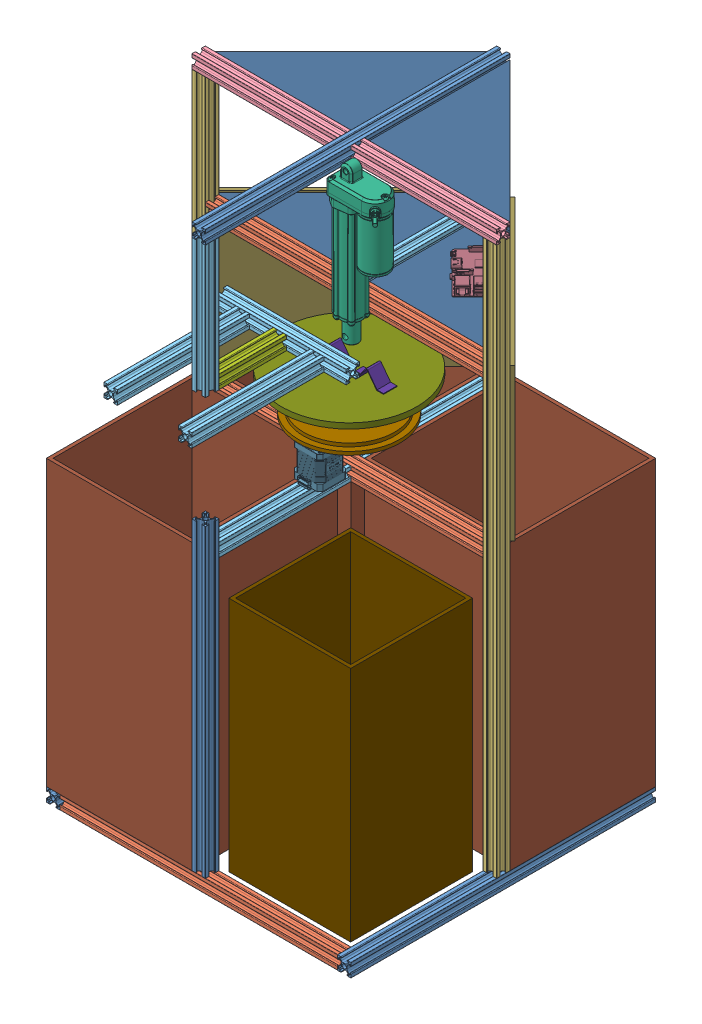
SolidWorks assembly 垃圾分类装配11.12, configuration 默认. Lengths in mm.
Overall size (454.8 850 529.91).
41 component instances, 18 part files, 92 mates.
Components (placement in the parent):
- 型材-1: 型材 [默认] at origin size (20 20 450)
- 型材-2: 型材 [默认] at (430 0 0) size (20 20 450)
- 450-40型材-1: 450-40型材 [默认] at (60 0 390) x (0 0 -1) z (1 0 0) size (20 20 410)
- 450-40型材-2: 450-40型材 [默认] at (60 0 -40) x (0 0 -1) z (1 0 0) size (20 20 410)
- 850-40型材-1: 850-40型材 [默认] at (0 770 175) x (1 0 0) z (0 -1 0) size (20 20 810)
- 850-40型材-2: 850-40型材 [默认] at (430 770 175) x (1 0 0) z (0 -1 0) size (20 20 810)
- 850-40型材-3: 850-40型材 [默认] at (215 770 -40) x (1 0 0) z (0 -1 0) size (20 20 810)
- 型材-3: 型材 [默认] at (215 830 0) size (20 20 450)
- 215型材-1: 215型材 [默认] at (274.9999 830 175) x (0 0 -1) z (1 0 0) size (20 20 215)
- 215型材-2: 215型材 [默认] at (40 830 175) x (0 0 -1) z (1 0 0) size (20 20 215)
- 450-40型材-3: 450-40型材 [默认] at (60 650 175) x (0 0 -1) z (1 0 0) size (20 20 410)
- 195型材-1: 195型材 [默认] at (215 650 20) size (20 20 195)
- 电动推杆-1: 电动推杆 [默认] at (248.0139 794.0379 210.699) x (-1 0 0) z (0 -1 0) size (89.01 54.01 228.74)
- 450-40型材-4: 450-40型材 [默认] at (60 420 175) x (0 0 -1) z (1 0 0) size (20 20 410)
- 195型材-2: 195型材 [默认] at (215 420 20) size (20 20 195)
- 型材-4: 型材 [默认] at (215 410 390) x (-1 0 0) z (0 -1 0) size (20 20 450)
- 195型材-3: 195型材 [默认] at (215 420 235) size (20 20 195)
- 195型材-4: 195型材 [默认] at (215 770 390) x (1 0 0) z (0 -1 0) size (20 20 195)
- 100型材-1: 100型材 [默认] at (215 635 330) size (20 20 100)
- 195型材-5: 195型材 [默认] at (167.5 635 270.0001) x (0 -1 0) z (1 0 0) size (20 20 195)
- 195型材-6: 195型材 [默认] at (269.9999 635 330) size (20 20 195)
- 195型材-7: 195型材 [默认] at (160 635 330) size (20 20 195)
- 小电机-1: 小电机 [默认] at (197.0585 516.4999 164.8) x (0 0 1) z (0 1 0) size (53.6 47.6 20)
- 电机上面圆盘-1: 电机上面圆盘 [默认] at (213.1083 486.2499 175.9459) x (0.178496 0 0.983941) z (-0.983941 0 0.178496) size (150 15.5 150)
- 三角木板-1: 三角木板 [默认] at (205 647.5 165) x (0 0 -1) z (1 0 0) size (215 5 215)
- 三角木板-2: 三角木板 [默认] at (225 647.5 165) size (215 5 215)
- 三角木板-3: 三角木板 [默认] at (225 827.5 165) size (215 5 215)
- 三角木板-4: 三角木板 [默认] at (205 827.5 165) x (0 0 -1) z (1 0 0) size (215 5 215)
- 纸盒-1: 纸盒 [默认] at (97.5 10 57.5) size (215 420 215)
- 纸盒-2: 纸盒 [默认] at (97.5 10 292.5) size (215 420 215)
- 纸盒-3: 纸盒 [默认] at (332.5 10 57.5) size (215 420 215)
- 纸盒-4: 纸盒 [默认] at (332.5 10 292.5) size (215 420 215) (hidden)
- 矩形木板-1: 矩形木板 [默认] at (332.871 542.5 54.3356) x (0.707107 0 0.707107) z (-0.707107 0 0.707107) size (304 225 5)
- 矩形木板-2: 矩形木板 [默认] at (96.5624 542.5 54.9021) x (-0.707107 0 0.707107) z (-0.707107 0 -0.707107) size (304 225 5)
- 电路板-1: 电路板 [默认] at (300.8487 658.8 72.0727) x (0.707107 0 0.707107) z (-0.707107 0 0.707107) size (92.18 27.81 66.27)
- 小电机新主动-1: 小电机新主动 [默认] at (215.8438 429.9999 221.7279) x (1 0 0) z (0 1 0) size (42.21 46.5 63.1)
- 舵机转向机构-1: 舵机转向机构 [默认] at (218.5585 496.4999 174.8) size (48 41 20)
- 舵机上面圆盘-1: 舵机上面圆盘 [默认] at (213.1083 537.4999 175.9459) size (200 8 200)
- 三角件-1: 三角件 [默认] at (189.2957 545.4999 174.8) size (50 20.33 20)
- 三角件-2: 三角件 [默认] at (247.8213 545.4999 174.8) size (50 20.33 20)
- 纸盒2-1: 纸盒2 [默认] at (323.6542 10 284.153) size (180 350 180)
Mates (geometry in assembly coordinates):
- 重合1: coincident aligned: plane of 型材-1 through (9.6 10 0) normal (0 1 0); plane of 型材-2 through (424.85 10 0) normal (0 1 0)
- 重合2: coincident aligned: plane of 型材-1 through (0 0 400) normal (0 0 1); plane of 型材-2 through (430 0 400) normal (0 0 1)
- 重合3: coincident aligned: plane of 型材-1 through (9.6 10 0) normal (0 1 0); plane of 450-40型材-1 through (60 10 395.15) normal (0 1 0)
- 重合4: coincident anti-aligned: plane of 型材-1 through (10 5.15 0) normal (1 0 0); plane of 450-40型材-1 through (10 0 390) normal (-1 0 0)
- 重合5: coincident aligned: plane of 型材-1 through (0 0 400) normal (0 0 1); plane of 450-40型材-1 through (60 9.6 400) normal (0 0 1)
- 重合6: coincident anti-aligned: plane of 型材-2 through (420 9.6 0) normal (-1 0 0); plane of 450-40型材-1 through (420 0 390) normal (1 0 0)
- 重合7: coincident aligned: plane of 型材-1 through (0 0 -50) normal (0 0 -1); plane of 450-40型材-2 through (60 -9.6 -50) normal (0 0 -1)
- 重合8: coincident aligned: plane of 型材-1 through (9.6 10 0) normal (0 1 0); plane of 450-40型材-2 through (60 10 -49.6) normal (0 1 0)
- 重合9: coincident anti-aligned: plane of 型材-1 through (10 -9.6 0) normal (1 0 0); plane of 450-40型材-2 through (10 0 -40) normal (-1 0 0)
- 重合10: coincident aligned: plane of 型材-1 through (10 5.15 0) normal (1 0 0); plane of 850-40型材-1 through (10 770 180.15) normal (1 0 0)
- 重合11: coincident anti-aligned: plane of 型材-1 through (-5.15 10 0) normal (0 1 0); plane of 850-40型材-1 through (0 10 175) normal (0 -1 0)
- 宽度1: width aligned: plane of 型材-1 through (0 0 400) normal (0 0 1); plane of 型材-1 through (0 0 -50) normal (0 0 -1); plane of 850-40型材-1 through (9.6 770 185) normal (0 0 1); plane of 850-40型材-1 through (5.15 770 165) normal (0 0 -1)
- 重合12: coincident aligned: plane of 850-40型材-1 through (5.15 770 165) normal (0 0 -1); plane of 850-40型材-2 through (420.4 770 165) normal (0 0 -1)
- 重合13: coincident aligned: plane of 型材-2 through (439.9999 5.15 0) normal (1 0 0); plane of 850-40型材-2 through (439.9999 770 165.4) normal (1 0 0)
- 重合14: coincident anti-aligned: plane of 型材-2 through (439.5999 10 0) normal (0 1 0); plane of 850-40型材-2 through (430 10 175) normal (0 -1 0)
- 重合15: coincident anti-aligned: plane of 450-40型材-2 through (60 10 -34.85) normal (0 1 0); plane of 850-40型材-3 through (215 10 -40) normal (0 -1 0)
- 重合17: coincident aligned: plane of 450-40型材-2 through (60 5.15 -50) normal (0 0 -1); plane of 850-40型材-3 through (205.4 770 -50) normal (0 0 -1)
- 宽度2: width anti-aligned: plane of 型材-1 through (-10 9.6 0) normal (-1 0 0); plane of 型材-2 through (439.9999 5.15 0) normal (1 0 0); plane of 850-40型材-3 through (225 770 -49.6) normal (1 0 0); plane of 850-40型材-3 through (205 770 -45.15) normal (-1 0 0)
- 重合18: coincident aligned: plane of 850-40型材-3 through (205.4 770 -50) normal (0 0 -1); plane of 型材-3 through (215 830 -50) normal (0 0 -1)
- 重合19: coincident anti-aligned: plane of 850-40型材-3 through (215 820 -40) normal (0 1 0); plane of 型材-3 through (220.15 820 0) normal (0 -1 0)
- 重合20: coincident aligned: plane of 850-40型材-3 through (225 770 -49.6) normal (1 0 0); plane of 型材-3 through (225 820.4 0) normal (1 0 0)
- 重合21: coincident aligned: plane of 850-40型材-2 through (439.9999 770 165.4) normal (1 0 0); plane of 215型材-1 through (439.9999 830 175) normal (1 0 0)
- 重合22: coincident anti-aligned: plane of 850-40型材-2 through (430 820 175) normal (0 1 0); plane of 215型材-1 through (274.9999 820 184.6) normal (0 -1 0)
- 重合23: coincident aligned: plane of 850-40型材-2 through (439.5999 770 185) normal (0 0 1); plane of 215型材-1 through (274.9999 824.85 185) normal (0 0 1)
- 重合24: coincident aligned: plane of 850-40型材-1 through (-10 770 169.85) normal (-1 0 0); plane of 215型材-2 through (-10 830 175) normal (-1 0 0)
- 重合25: coincident anti-aligned: plane of 850-40型材-1 through (0 820 175) normal (0 1 0); plane of 215型材-2 through (40 820 169.85) normal (0 -1 0)
- 重合26: coincident aligned: plane of 850-40型材-1 through (-9.6 770 165) normal (0 0 -1); plane of 215型材-2 through (40 820.4 165) normal (0 0 -1)
- 重合27: coincident aligned: plane of 850-40型材-1 through (9.6 770 185) normal (0 0 1); plane of 450-40型材-3 through (60 659.6 185) normal (0 0 1)
- 重合28: coincident anti-aligned: plane of 850-40型材-1 through (10 770 180.15) normal (1 0 0); plane of 450-40型材-3 through (10 650 175) normal (-1 0 0)
- 重合29: coincident anti-aligned: plane of 850-40型材-3 through (224.6 770 -30) normal (0 0 1); plane of 195型材-1 through (215 650 -30) normal (0 0 -1)
- 重合30: coincident aligned: plane of 450-40型材-3 through (60 660 165.4) normal (0 1 0); plane of 195型材-1 through (224.6 660 20) normal (0 1 0)
- 重合31: coincident aligned: plane of 850-40型材-3 through (225 770 -34.85) normal (1 0 0); plane of 195型材-1 through (225 655.15 20) normal (1 0 0)
- 平行1: parallel aligned: plane of 215型材-1 through (274.9999 839.5999 185) normal (0 0 1); plane of 电动推杆-1 through (276.3764 799.0379 220.7552) normal (0 0 1)
- 平行2: parallel aligned: plane of 型材-3 through (205 824.85 0) normal (-1 0 0); plane of 电动推杆-1 through (221.3764 799.0379 186.7552) normal (-1 0 0)
- 重合32: coincident aligned: plane of 450-40型材-3 through (60 659.6 185) normal (0 0 1); plane of 450-40型材-4 through (60 429.5999 185) normal (0 0 1)
- 重合33: coincident anti-aligned: plane of 850-40型材-1 through (10 770 180.15) normal (1 0 0); plane of 450-40型材-4 through (10 420 175) normal (-1 0 0)
- 重合34: coincident aligned: plane of 450-40型材-4 through (60 429.9999 165.4) normal (0 1 0); plane of 195型材-2 through (224.6 429.9999 20) normal (0 1 0)
- 重合35: coincident aligned: plane of 850-40型材-3 through (225 770 -34.85) normal (1 0 0); plane of 195型材-2 through (225 425.1499 20) normal (1 0 0)
- 重合36: coincident anti-aligned: plane of 850-40型材-3 through (224.6 770 -30) normal (0 0 1); plane of 195型材-2 through (215 420 -30) normal (0 0 -1)
- 重合37: coincident anti-aligned: plane of 450-40型材-1 through (60 10 380.4) normal (0 1 0); plane of 型材-4 through (215 10 390) normal (0 -1 0)
- 重合38: coincident aligned: plane of 450-40型材-1 through (60 9.6 400) normal (0 0 1); plane of 型材-4 through (224.6 410 400) normal (0 0 1)
- 重合39: coincident aligned: plane of 195型材-2 through (205 429.5999 20) normal (-1 0 0); plane of 型材-4 through (205 410 399.6) normal (-1 0 0)
- 重合40: coincident: plane of 195型材-2 through (209.85 429.9999 20) normal (0 1 0); plane of 195型材-3 through (209.85 429.9999 235) normal (0 1 0)
- 重合41: coincident aligned: plane of 195型材-2 through (205 429.5999 20) normal (-1 0 0); plane of 195型材-3 through (205 429.5999 235) normal (-1 0 0)
- 重合42: coincident anti-aligned: plane of 450-40型材-4 through (60 429.5999 185) normal (0 0 1); plane of 195型材-3 through (215 420 185) normal (0 0 -1)
- 重合43: coincident aligned: plane of 型材-3 through (215 830 400) normal (0 0 1); plane of 195型材-4 through (224.6 770 400) normal (0 0 1)
- 重合44: coincident aligned: plane of 型材-3 through (225 820.4 0) normal (1 0 0); plane of 195型材-4 through (225 770 395.15) normal (1 0 0)
- 重合45: coincident anti-aligned: plane of 型材-3 through (220.15 820 0) normal (0 -1 0); plane of 195型材-4 through (215 820 390) normal (0 1 0)
- 重合46: coincident aligned: plane of 195型材-4 through (225 770 380.4) normal (1 0 0); plane of 100型材-1 through (225 640.1499 330) normal (1 0 0)
- 重合47: coincident anti-aligned: plane of 195型材-4 through (220.15 770 380) normal (0 0 -1); plane of 100型材-1 through (215 635 380) normal (0 0 1)
- 重合48: coincident aligned: plane of 195型材-4 through (215 625 390) normal (0 -1 0); plane of 100型材-1 through (220.15 625 330) normal (0 -1 0)
- 重合49: coincident anti-aligned: plane of 100型材-1 through (215 635 280) normal (0 0 -1); plane of 195型材-5 through (167.5 644.5999 280) normal (0 0 1)
- 重合50: coincident aligned: plane of 100型材-1 through (224.6 644.9999 330) normal (0 1 0); plane of 195型材-5 through (167.5 644.9999 275.15) normal (0 1 0)
- 宽度3: width anti-aligned: plane of 195型材-5 through (312.5 635 270.0001) normal (1 0 0); plane of 195型材-5 through (117.5 635 270.0001) normal (-1 0 0); plane of 100型材-1 through (205 644.5999 330) normal (-1 0 0); plane of 100型材-1 through (225 640.1499 330) normal (1 0 0)
- 重合51: coincident aligned: plane of 195型材-5 through (167.5 644.9999 275.15) normal (0 1 0); plane of 195型材-6 through (279.5999 644.9999 330) normal (0 1 0)
- 重合52: coincident anti-aligned: plane of 195型材-5 through (167.5 644.5999 280) normal (0 0 1); plane of 195型材-6 through (269.9999 635 280) normal (0 0 -1)
- 重合53: coincident aligned: plane of 195型材-5 through (167.5 644.9999 260.4001) normal (0 1 0); plane of 195型材-7 through (169.6 644.9999 330) normal (0 1 0)
- 重合54: coincident anti-aligned: plane of 195型材-5 through (167.5 644.5999 280) normal (0 0 1); plane of 195型材-7 through (160 635 280) normal (0 0 -1)
- 距离1: distance = 35 mm anti-aligned: plane of 195型材-6 through (260 644.5999 330) normal (-1 0 0); plane of 100型材-1 through (225 640.1499 330) normal (1 0 0)
- 距离3: distance = 35 mm anti-aligned: plane of 195型材-7 through (170 640.1499 330) normal (1 0 0); plane of 100型材-1 through (205 644.5999 330) normal (-1 0 0)
- 宽度5: width anti-aligned: plane of 195型材-1 through (205.4 640 20) normal (0 -1 0); plane of 195型材-1 through (209.85 660 20) normal (0 1 0); plane of 三角木板-1 through (205 652.5 165) normal (0 1 0); plane of 三角木板-1 through (205 647.5 165) normal (0 -1 0)
- 重合59: coincident anti-aligned: plane of 195型材-1 through (205 659.6 20) normal (-1 0 0); plane of 三角木板-1 through (205 652.5 165) normal (1 0 0)
- 重合60: coincident anti-aligned: plane of 450-40型材-3 through (60 655.15 165) normal (0 0 -1); plane of 三角木板-1 through (205 652.5 165) normal (0 0 1)
- 重合61: coincident aligned: plane of 三角木板-1 through (205 652.5 165) normal (0 1 0); plane of 三角木板-2 through (225 652.5 165) normal (0 1 0)
- 重合62: coincident anti-aligned: plane of 195型材-1 through (225 655.15 20) normal (1 0 0); plane of 三角木板-2 through (225 652.5 165) normal (-1 0 0)
- 重合63: coincident anti-aligned: plane of 450-40型材-3 through (60 655.15 165) normal (0 0 -1); plane of 三角木板-2 through (225 652.5 165) normal (0 0 1)
- 距离4: distance = 160 mm anti-aligned: plane of 215型材-2 through (40 820 169.85) normal (0 -1 0); plane of 450-40型材-3 through (60 660 180.15) normal (0 1 0)
- 距离5: distance = 400 mm: plane of 195型材-2 through (205.4 410 20) normal (0 -1 0); plane of 450-40型材-2 through (60 10 -34.85) normal (0 1 0)
- 重合66: coincident anti-aligned: plane of 450-40型材-2 through (60 10 -34.85) normal (0 1 0); plane of 纸盒-1 through (97.5 10 57.5) normal (0 -1 0)
- 重合67: coincident aligned: plane of 型材-1 through (-10 9.6 0) normal (-1 0 0); plane of 纸盒-1 through (-10 15 165) normal (-1 0 0)
- 重合68: coincident aligned: plane of 450-40型材-2 through (60 5.15 -50) normal (0 0 -1); plane of 纸盒-1 through (205 15 -50) normal (0 0 -1)
- 重合69: coincident anti-aligned: plane of 三角木板-3 through (225 832.5 -50) normal (0.707107 0 -0.707107); plane of 矩形木板-1 through (331.1033 542.5 56.1033) normal (-0.707107 0 0.707107)
- 重合71: coincident anti-aligned: plane of 纸盒-3 through (332.5 430 57.5) normal (0 1 0); plane of 矩形木板-1 through (438.5835 430 163.5836) normal (0 -1 0)
- 重合72: coincident anti-aligned: plane of 三角木板-1 through (-10 652.5 165) normal (-0.707107 0 -0.707107); plane of 矩形木板-2 through (98.3302 542.5 56.6699) normal (0.707107 0 0.707107)
- 重合73: coincident aligned: plane of 矩形木板-1 through (438.5835 655 163.5836) normal (0 1 0); plane of 矩形木板-2 through (-12.6856 655 160.6146) normal (0 1 0)
- 距离6: distance = 5 mm anti-aligned: plane of 电路板-1 through (311.1017 657.5 118.3882) normal (0 -1 0); plane of 三角木板-2 through (225 652.5 165) normal (0 1 0)
- 平行3: parallel anti-aligned: plane of 矩形木板-1 through (331.1033 542.5 56.1033) normal (-0.707107 0 0.707107); plane of 电路板-1 through (348.932 657.5 80.558) normal (0.707107 0 -0.707107)
- 重合74: coincident: plane of 195型材-3 through (224.6 429.9999 235) normal (0 1 0); plane of 小电机新主动-1 through (215.8438 429.9999 221.7279) normal (0 -1 0)
- 平行4: parallel aligned: plane of 纸盒-4 through (230 430 395) normal (1 0 0); plane of 小电机新主动-1 through (236.8438 429.9999 238.2279) normal (1 0 0)
- 重合76: coincident: plane of 小电机-1 through (233.6585 496.4999 164.8) normal (0 -1 0); plane of 电机上面圆盘-1 through (201.1112 496.4999 109.8132) normal (0 1 0)
- 重合78: coincident: plane of 电机上面圆盘-1 through (213.1083 492.9999 175.9459) normal (0 -1 0); plane of 小电机新主动-1 through (215.8438 492.9999 221.7279) normal (0 1 0)
- 同心1: concentric anti-aligned: cylinder of 小电机-1 through (237.7585 506.4999 174.8) axis (-1 0 0) radius 4.5; cylinder of 舵机转向机构-1 through (240.0585 506.4999 174.8) axis (1 0 0) radius 10
- 重合79: coincident anti-aligned: plane of 小电机-1 through (197.0585 496.4999 164.8) normal (-1 0 0); plane of 舵机转向机构-1 through (197.0585 496.4999 184.8) normal (1 0 0)
- 平行5: parallel aligned: plane of 电机上面圆盘-1 through (213.1083 491.2499 175.9459) normal (0 1 0); plane of 舵机转向机构-1 through (199.0585 537.4999 184.8) normal (0 1 0)
- 重合80: coincident anti-aligned: plane of 舵机转向机构-1 through (199.0585 537.4999 184.8) normal (0 1 0); plane of 舵机上面圆盘-1 through (213.1083 537.4999 175.9459) normal (0 -1 0)
- 同心2: concentric aligned: cylinder of 电机上面圆盘-1 through (213.1083 491.2499 175.9459) axis (0 -1 0) radius 75; cylinder of 舵机上面圆盘-1 through (213.1083 545.4999 175.9459) axis (0 -1 0) radius 100
- 重合81: coincident anti-aligned: plane of 舵机上面圆盘-1 through (213.1083 545.4999 175.9459) normal (0 1 0); plane of 三角件-1 through (204.2957 545.4999 184.8) normal (0 -1 0)
- 重合82: coincident aligned: plane of 三角件-1 through (204.7957 546.4999 184.8) normal (0 1 0); plane of 三角件-2 through (232.3213 546.4999 184.8) normal (0 1 0)
- 重合83: coincident aligned: plane of 三角件-1 through (189.2957 545.4999 184.8) normal (0 0 1); plane of 三角件-2 through (247.8213 545.4999 184.8) normal (0 0 1)
- 重合84: coincident aligned: plane of 舵机转向机构-1 through (199.0585 534.4999 184.8) normal (0 0 1); plane of 三角件-1 through (189.2957 545.4999 184.8) normal (0 0 1)
- 宽度6: width anti-aligned: plane of 舵机转向机构-1 through (196.0585 496.4999 184.8) normal (-1 0 0); plane of 舵机转向机构-1 through (241.0585 534.4999 184.8) normal (1 0 0); plane of 三角件-1 through (214.2957 545.4999 184.8) normal (1 0 0); plane of 三角件-2 through (222.8213 545.4999 184.8) normal (-1 0 0)
- 重合85: coincident aligned: plane of 纸盒-2 through (97.5 10 292.5) normal (0 -1 0); plane of 纸盒2-1 through (323.6542 10 284.153) normal (0 -1 0)
